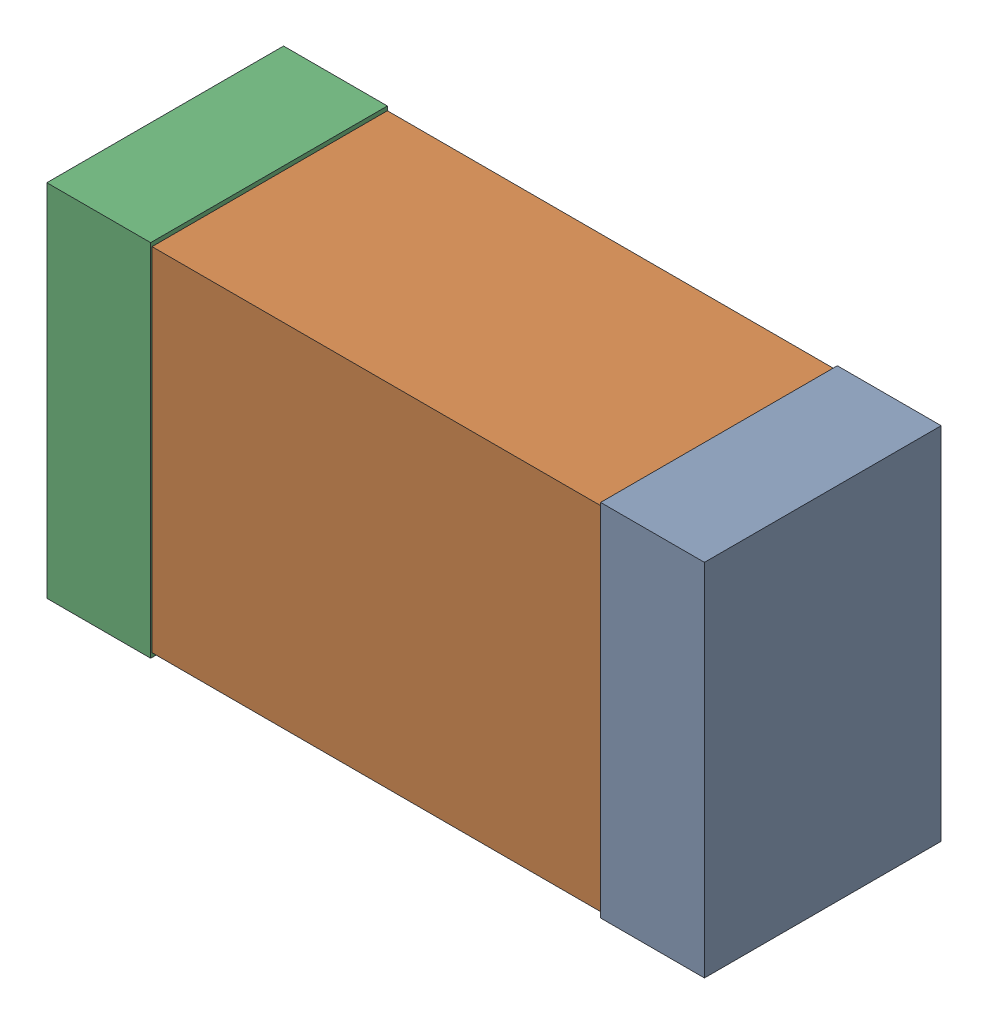
SolidWorks assembly C4Kanaloa_v2.0.0_Motor_1, configuration Default. Lengths in mm.
Overall size (2.38 1.3 0.85).
6 component instances, 2 part files, 0 mates.
Components (placement in the parent):
- 352877648-1: 352877648 [Default] at (74.66 109.728 0) size (0.38 1.3 0.85)
  - Extruded_14-1: Extruded_14 [Default] at origin size (0.38 1.3 0.85)
- 352877904-1: 352877904 [Default] at (73.66 109.728 0) size (2.2 1.27 0.85)
  - Extruded_18-1: Extruded_18 [Default] at origin size (2.2 1.27 0.85)
- 352877648-2: 352877648 [Default] at (72.66 109.728 0) size (0.38 1.3 0.85)
  - Extruded_14-1: Extruded_14 [Default] at origin size (0.38 1.3 0.85)
